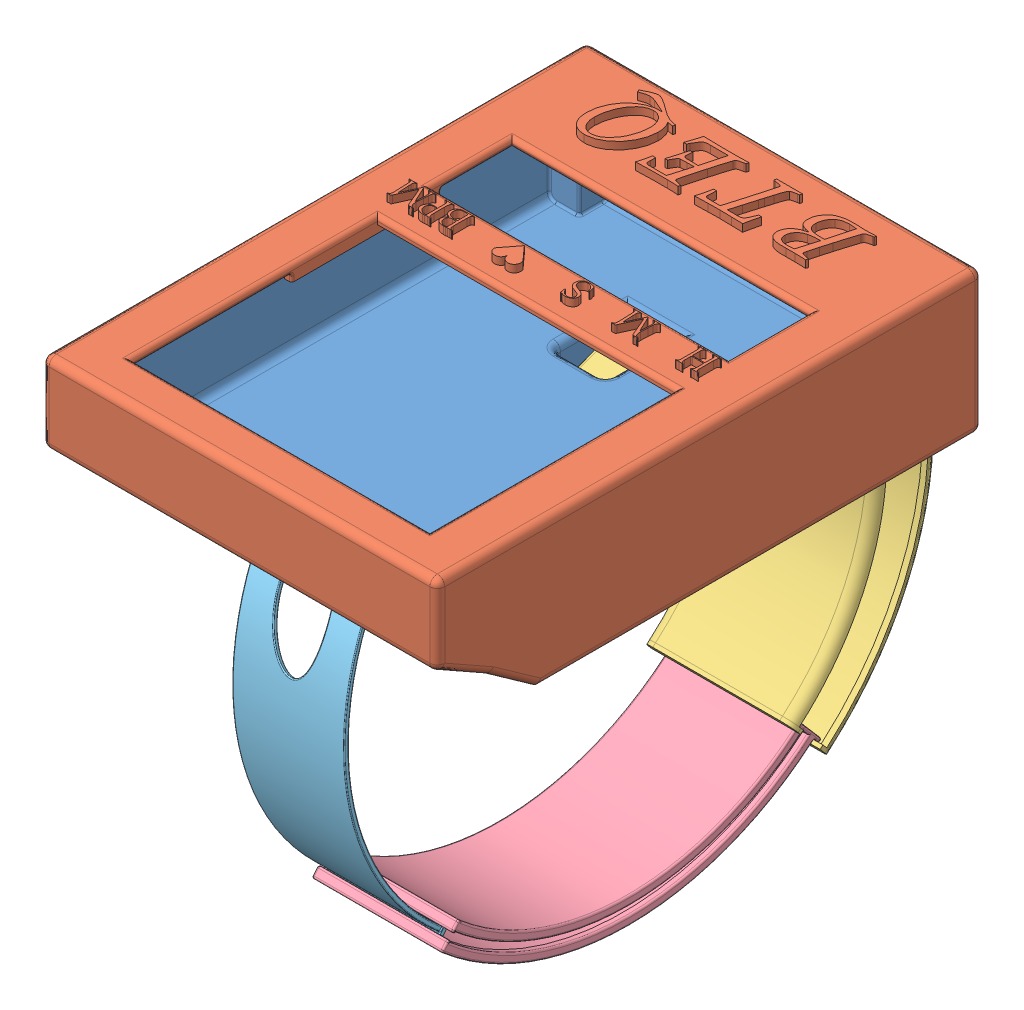
SolidWorks assembly WatchDraft2Assembly, configuration Default. Lengths in mm.
Overall size (54.2 75.41 84.02).
5 component instances, 5 part files, 14 mates.
Components (placement in the parent):
- Connector-1: Connector [Default] at (-48.7606 -9.552 21.1053) size (50 18 70)
- Cover-1: Cover [Default] at (-22.7606 -9.552 26.1053) x (0 0 1) z (-1 0 0) size (73 20 54.2)
- LeftBand-2: LeftBand [Default] at (-48.7606 -5.552 1.1052) x (0 0 -1) z (1 0 0) size (38.97 52.43 23.74)
- Intermediate Band-1: Intermediate Band [Default] at (-48.3106 -37.7216 -1.2979) x (0 -0.988746 -0.149603) z (1 0 0) size (15.71 50.07 17.54)
- RightBand-1: RightBand [Default] at (-48.7606 -44.9103 30.1501) x (0 -0.295838 0.955238) z (1 0 0) size (13.68 48.28 15.2)
Mates (geometry in assembly coordinates):
- Coincident1: coincident: plane of Connector-1 through (-48.7606 8.448 21.1053) normal (0 1 0); plane of Cover-1 through (-73.7606 8.448 61.1053) normal (0 -1 0)
- Coincident2: coincident: plane of Connector-1 through (-73.7606 -1.552 -8.8947) normal (-1 0 0); plane of Cover-1 through (-73.7606 -9.552 26.1053) normal (1 0 0)
- Coincident3: coincident: plane of Connector-1 through (-23.7606 8.448 61.1053) normal (0 0 1); plane of Cover-1 through (-73.7606 -1.552 61.1053) normal (0 0 -1)
- Coincident4: coincident: plane of Connector-1 through (-48.7606 -9.552 8.1053) normal (0 0 -1); plane of LeftBand-2 through (-48.7606 -5.552 8.1053) normal (0 0 1)
- Coincident5: coincident: plane of Connector-1 through (-40.2606 -8.552 8.1053) normal (0 1 0); plane of LeftBand-2 through (-58.7606 -8.552 1.1053) normal (0 -1 0)
- Distance1: distance = 0.5 mm: plane of LeftBand-2 through (-45.7606 -8.552 16.6053) normal (1 0 0); plane of Connector-1 through (-45.2606 -4.552 16.1053) normal (-1 0 0)
- Coincident7: coincident: plane of LeftBand-2 through (-58.7606 -21.6566 19.7922) normal (0 0.652826 -0.757508); plane of Intermediate Band-1 through (-48.3106 -41.3045 2.8595) normal (0 -0.652826 0.757508)
- Tangent1: tangent: plane of LeftBand-2 through (-48.7606 -21.6565 19.7922) normal (0 0.652826 -0.757508); cylinder of Intermediate Band-1 through (-57.0606 -48.4495 -3.6282) axis (-1 0 0) radius 0.25
- Coincident8: coincident: plane of LeftBand-2 through (-58.7606 -21.6566 19.7922) normal (0 0.652826 -0.757508); plane of Intermediate Band-1 through (-48.3106 -41.3045 2.8595) normal (0 -0.652826 0.757508)
- Concentric1: concentric: cylinder of LeftBand-2 through (-48.7606 -23.0338 18.6052) axis (1 0 0) radius 33.3182; cylinder of Intermediate Band-1 through (-48.3106 -23.0338 18.6052) axis (1 0 0) radius 34.5172
- Coincident9: coincident: plane of LeftBand-2 through (-39.5606 -47.6666 -2.6234) normal (-1 0 0); plane of Intermediate Band-1 through (-39.5606 -49.2674 41.0382) normal (1 0 0)
- Concentric2: concentric: cylinder of Intermediate Band-1 through (-48.3106 -23.0338 18.6052) axis (1 0 0) radius 35.3172; cylinder of RightBand-1 through (-48.7606 -23.0338 18.6052) axis (1 0 0) radius 35.8682
- Coincident10: coincident: plane of Intermediate Band-1 through (-48.3106 -21.6868 17.4534) normal (0 -0.649907 -0.760014); plane of RightBand-1 through (-48.7606 -41.3726 34.2872) normal (0 0.649907 0.760014)
- Coincident12: coincident: plane of Intermediate Band-1 through (-56.2606 -49.2674 41.0382) normal (1 0 0); plane of RightBand-1 through (-56.2606 -4.0069 49.0108) normal (-1 0 0)
